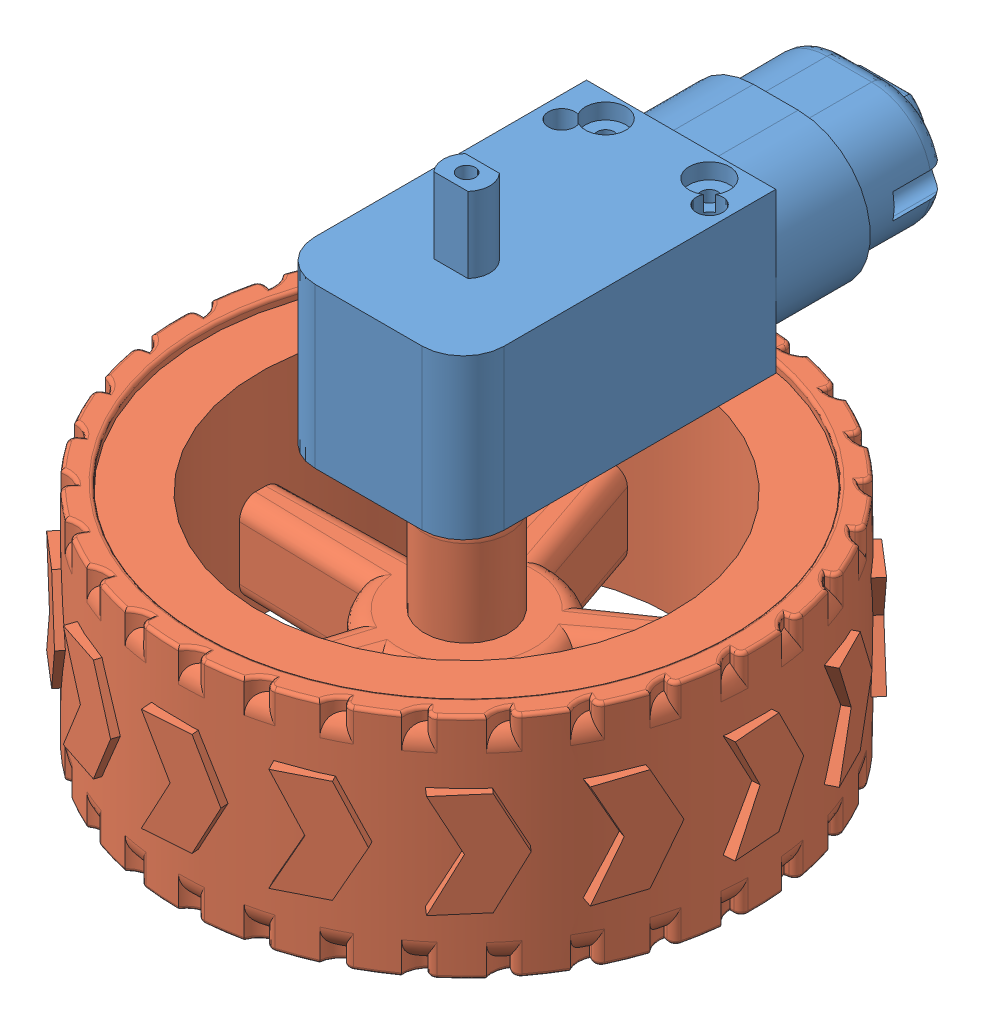
SolidWorks assembly Assem Motor Dc 2, configuration Default. Lengths in mm.
Overall size (87.86 58.76 93.93).
2 component instances, 2 part files, 2 mates.
Components (placement in the parent):
- Motor Dc-1: Motor Dc [Default] at (28.0001 31.0367 57.5133) size (22.4 36.72 61.5)
- Roda kanan 2-1: Roda kanan 2 [Default] at (28.1101 4.1767 64.5133) x (-0.31232 0 0.949977) z (0.949977 0 0.31232) size (69.6 27.07 69.6)
Mates (geometry in assembly coordinates):
- Concentric2: concentric aligned: cylinder of Motor Dc-1 through (28.1101 12.6767 64.5133) axis (0 1 0) radius 2.75; circle of Roda kanan 2-1
- Distance3: distance = 8 mm anti-aligned: plane of Roda kanan 2-1 through (28.1101 4.6767 64.5133) normal (0 1 0); plane of Motor Dc-1 through (28.1101 12.6767 64.5133) normal (0 -1 0)
